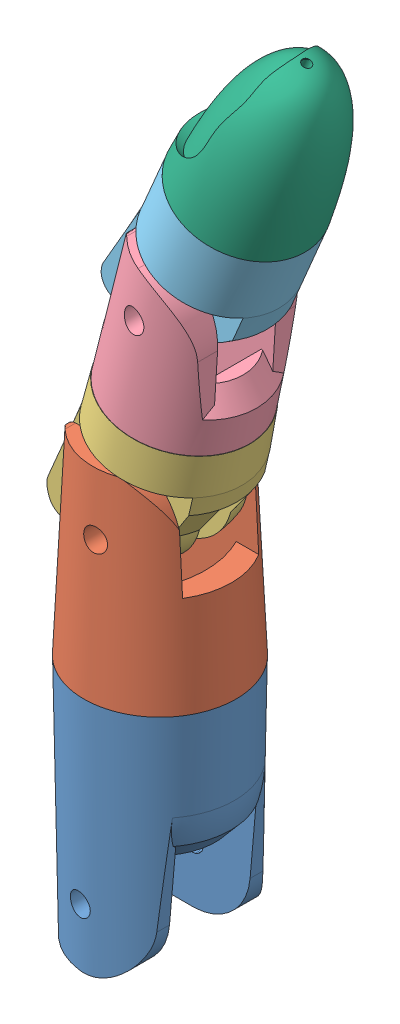
SolidWorks assembly deget ia montaj, configuration Default. Lengths in mm.
Overall size (32.62 95.22 17).
6 component instances, 6 part files, 18 mates.
Components (placement in the parent):
- deget ia 3-4-1: deget ia 3-4 [Default] x (0 0 -1) z (-1 0 0) size (17 27 17)
- deget ia 3-3-1: deget ia 3-3 [Default] x (0 -1 0) z (-1 0 0) size (22 17 17)
- deget ia 3-5-1: deget ia 3-5 [Default] at (2.7147 27.1045 0) x (-0.225156 -0.974323 0) z (0 0 -1) size (17.26 16.52 15.41)
- deget ia 3-6-1: deget ia 3-6 [Default] at (6.3172 42.6936 0) x (-0.225156 -0.974323 0) z (0.974323 -0.225156 0) size (16 15.32 14.93)
- deget ia 3-2-1: deget ia 3-2 [Default] at (9.7593 49.8172 0) x (-0.920423 0.390924 0) z (-0.390924 -0.920423 0) size (14.75 14.1 18.07)
- deget ia-1: deget ia [Default] at (9.7556 49.8188 0) x (0 0 1) z (-0.920423 0.390924 0) size (14.02 17.03 14.02)
Mates (geometry in assembly coordinates):
- Coincident1: coincident anti-aligned: plane of deget ia 3-4-1 through (0 0 0) normal (0 0 -1)
- Coincident2: coincident anti-aligned: plane of deget ia 3-4-1 through (0 0 0) normal (-1 0 0)
- Coincident3: coincident anti-aligned: plane of deget ia 3-4-1 through (0 0 0) normal (0 -1 0)
- Concentric1: concentric anti-aligned: cone of deget ia 3-4-1 through (0 0 0) axis (0 -1 0); cone of deget ia 3-3-1 through (0 22 0) axis (0 1 0)
- Coincident4: coincident anti-aligned: plane of deget ia 3-4-1 through (0 0 0) normal (0 1 0); plane of deget ia 3-3-1 through (0 0 0) normal (0 -1 0)
- Coincident5: coincident aligned: plane of deget ia 3-4-1 through (0 0 0) normal (-1 0 0); plane of deget ia 3-3-1 through (0 0 0) normal (-1 0 0)
- Concentric2: concentric anti-aligned: cylinder of deget ia 3-3-1 through (0.5 15.3 -10) axis (0 0 1) radius 1.25; cylinder of deget ia 3-5-1 through (0.5 15.3 7.7071) axis (0 0 -1) radius 1.25
- Coincident6: coincident anti-aligned: plane of deget ia 3-3-1 through (10 24.98 4.25) normal (0 0 -1); plane of deget ia 3-5-1 through (-0.7514 17.3422 4.25) normal (0 0 1)
- LimitAngle1: limit planar angle = 2.91449 rad anti-aligned: plane of deget ia 3-3-1 through (0 0 0) normal (-1 0 0); plane of deget ia 3-5-1 through (2.7147 27.1045 0) normal (-0.974323 0.225156 0)
- Concentric3: concentric aligned: cone of deget ia 3-5-1 through (2.7147 27.1045 0) axis (0.225156 0.974323 0); cone of deget ia 3-6-1 through (2.2644 25.1558 0) axis (0.225156 0.974323 0)
- Coincident9: coincident anti-aligned: plane of deget ia 3-5-1 through (2.7147 27.1045 0) normal (0.225156 0.974323 0); plane of deget ia 3-6-1 through (-4.5927 28.7931 23.25) normal (-0.225156 -0.974323 0)
- Coincident10: coincident anti-aligned: plane of deget ia 3-5-1 through (2.7147 27.1045 0) normal (-0.974323 0.225156 0); plane of deget ia 3-6-1 through (6.3172 42.6936 0) normal (0.974323 -0.225156 0)
- Concentric4: concentric aligned: cylinder of deget ia 3-6-1 through (4.2171 38.0472 7.5) axis (0 0 -1) radius 1.25; cylinder of deget ia 3-2-1 through (4.2171 38.0472 7.05) axis (0 0 -1) radius 1.25
- Width1: width anti-aligned: plane of deget ia 3-2-1 through (-1.325 37.105 3.25) normal (0 0 1); plane of deget ia 3-6-1 through (-1.325 37.105 -3.25) normal (0 0 -1); plane of deget ia 3-2-1 through (6.3172 42.6936 3.25) normal (0 0 -1); plane of deget ia 3-6-1 through (6.3172 42.6936 -3.25) normal (0 0 1)
- LimitAngle2: limit planar angle = 2.96706 rad aligned: plane of deget ia 3-6-1 through (6.3172 42.6936 0) normal (0.974323 -0.225156 0); plane of deget ia 3-2-1 through (9.7593 49.8172 0) normal (-0.920423 0.390924 0)
- Coincident11: coincident anti-aligned: cylinder of deget ia 3-2-1 through (6.8274 42.914 0) axis (0.390924 0.920423 0) radius 7; circle of deget ia-1
- Coincident12: coincident anti-aligned: plane of deget ia 3-2-1 through (9.7593 49.8172 0) normal (0.390924 0.920423 0); plane of deget ia-1 through (14.2472 47.9111 0) normal (-0.390924 -0.920423 0)
- Parallel1: parallel aligned: plane of deget ia 3-2-1 through (9.7593 49.8172 0) normal (-0.920423 0.390924 0); plane of deget ia-1 through (9.7556 49.8188 0) normal (-0.920423 0.390924 0)
